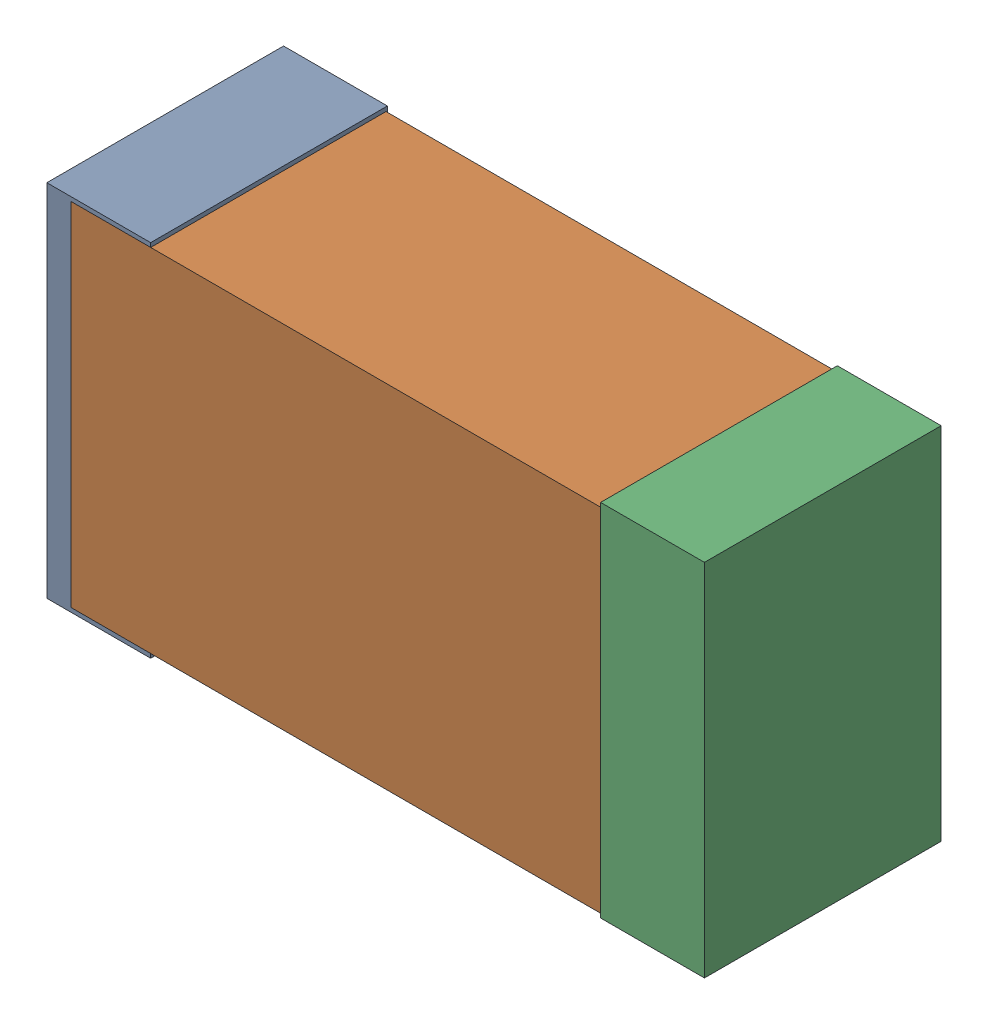
SolidWorks assembly USB01_C11, configuration Default. Lengths in mm.
Overall size (2.38 1.3 0.85).
6 component instances, 2 part files, 0 mates.
Components (placement in the parent):
- 384311232-1: 384311232 [Default] at (172.99 73.279 -1.9574) size (0.38 1.3 0.85)
  - Extruded_8-1: Extruded_8 [Default] at origin size (0.38 1.3 0.85)
- 384311360-1: 384311360 [Default] at (173.99 73.279 -1.9524) size (2.2 1.27 0.85)
  - Extruded_9-1: Extruded_9 [Default] at origin size (2.2 1.27 0.85)
- 384311232-2: 384311232 [Default] at (174.99 73.279 -1.9574) size (0.38 1.3 0.85)
  - Extruded_8-1: Extruded_8 [Default] at origin size (0.38 1.3 0.85)
